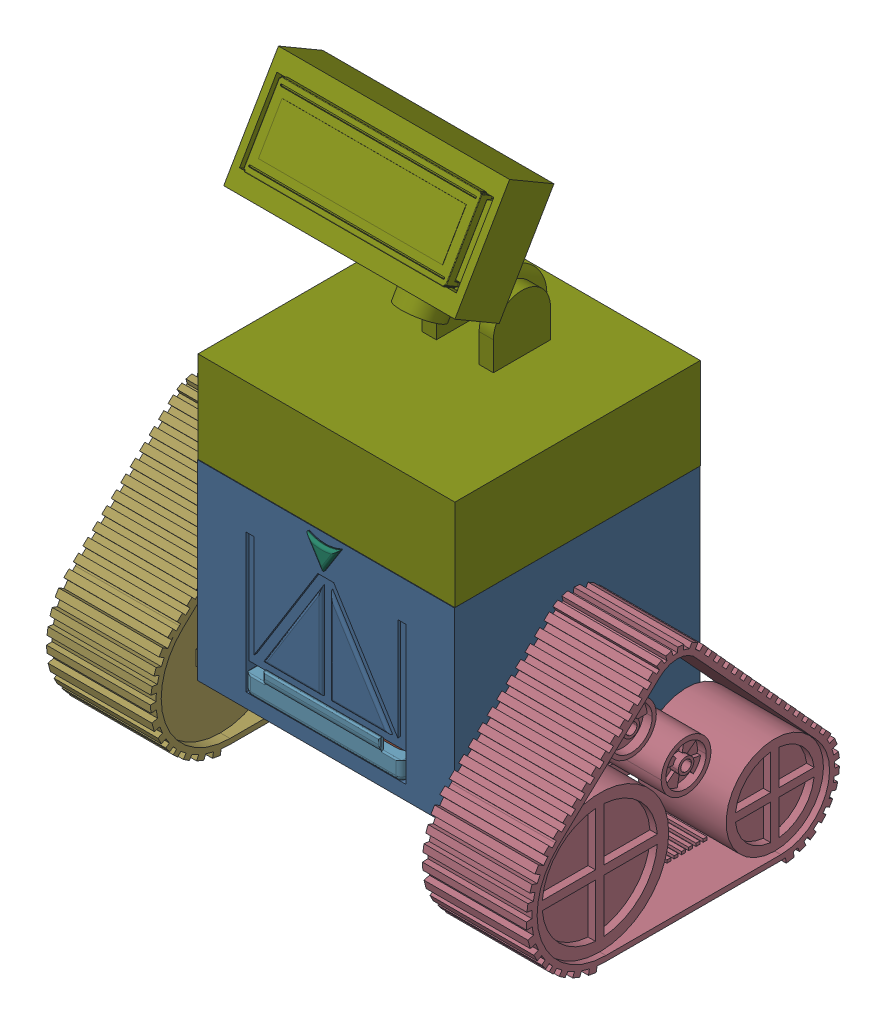
SolidWorks assembly Lower Body, configuration Default. Lengths in mm.
Overall size (168.14 212.39 109.67).
172 component instances, 52 part files, 15 mates.
Components (placement in the parent):
- Clock PCB.step-1: Clock PCB.step [Default] at (-3.837 -6.133 58.5856) size (81.95 80 25.5)
  - Board.step-1: Board.step [Default] at origin size (80 80 0.41)
    - Open CASCADE STEP translator 6.8 1.1.1.step-1: Open CASCADE STEP translator 6.8 1.1.1.step [Default] at (0 0 -0.4115) size (80 80 0.41)
  - XTAL1.step-1: XTAL1.step [Default] at origin size (11.36 4.66 3.61)
    - 6606830048.step-1: 6606830048.step [Default] at (28.0499 41.0499 0) size (11.36 4.66 1.01)
      - Extruded.step-1: Extruded.step [Default] at origin size (11.36 4.66 1.01)
    - 6606829968.step-1: 6606829968.step [Default] at (28.0499 41.0501 1) size (10.05 3.71 2.61)
      - Extruded-0.step-1: Extruded-0.step [Default] at origin size (10.05 3.71 2.61)
  - U2.step-1: U2.step [Default] at origin size (10.5 4.7 16.2)
    - 6606829888.step-1: 6606829888.step [Default] at (7.95 27.55 13.05) size (10.4 1.3 6.65)
      - Extruded-1.step-1: Extruded-1.step [Default] at origin size (10.4 1.3 6.65)
    - 6606829728.step-1: 6606829728.step [Default] at (7.95 25.9 3.5) size (10.5 4.7 9.55)
      - Extruded-2.step-1: Extruded-2.step [Default] at origin size (10.5 4.7 9.55)
  - U1.step-1: U1.step [Default] at origin size (63.7 16.03 14.45)
    - User_Library-ZIF-Socket-28-pin.step-1: User_Library-ZIF-Socket-28-pin.step [Default] at (43.5 28.05 0) x (1 0 0) z (0 0 1) size (63.7 16.03 14.45)
      - Contacts.step-1: Contacts.step [Default] at origin size (34.37 11.24 1.5)
      - Pins001.step-1: Pins001.step [Default] at origin size (33.87 8.47 3)
      - Screw002.step-1: Screw002.step [Default] at origin size (2.8 2.8 2)
      - Bottom-Shape.step-1: Bottom-Shape.step [Default] at origin size (50.4 15.02 8.11)
      - Lever-Tip.step-1: Lever-Tip.step [Default] at origin size (7 4.8 4.8)
      - Top-Shape.step-1: Top-Shape.step [Default] at origin size (50.4 15.02 3.8)
      - Push-Bar.step-1: Push-Bar.step [Default] at origin size (3.85 15.02 3.7)
      - Lever-Bar.step-1: Lever-Bar.step [Default] at origin size (19.2 11.43 1.62)
      - Screw001.step-1: Screw001.step [Default] at origin size (2.8 2.8 2)
  - Q1.step-1: Q1.step [Default] at origin size (3.05 4.08 12.8)
    - BC547-B.step-1: BC547-B.step [Default] at (72 53.1536 7) x (0 1 0) z (0 0 -1) size (4.08 3.05 12.8)
  - P3.step-1: P3.step [Default] at origin size (2.54 10.16 11.54)
    - 61300411121.step-1: 61300411121.step [Default] at (76.2999 22.6001 1.3) x (0 1 0) z (1 0 0) size (10.16 11.54 2.54)
      - 6130xx11121_PIN.step-1: 6130xx11121_PIN.step [Default] at (-3.81 1.5 0) x (1 0 0) z (0 -1 0) size (0.64 0.64 11.54)
      - 6130xx11121_PIN.step-2: 6130xx11121_PIN.step [Default] at (-1.27 1.5 0) x (1 0 0) z (0 -1 0) size (0.64 0.64 11.54)
      - 6130xx11121_PIN.step-3: 6130xx11121_PIN.step [Default] at (1.27 1.5 0) x (1 0 0) z (0 -1 0) size (0.64 0.64 11.54)
      - 6130xx11121_PIN.step-4: 6130xx11121_PIN.step [Default] at (3.81 1.5 0) x (1 0 0) z (0 -1 0) size (0.64 0.64 11.54)
      - 61300411121-3.step-1: 61300411121-3.step [Default] at origin size (10.16 2.54 2.54)
  - P2.step-1: P2.step [Default] at origin size (17.78 2.54 11.54)
    - 61300711121.step-1: 61300711121.step [Default] at (39.9599 3.8999 1.3) x (-1 0 0) z (0 1 0) size (17.78 11.54 2.54)
      - 6130xx11121_PIN-4.step-1: 6130xx11121_PIN-4.step [Default] at (-7.62 1.5 0) x (1 0 0) z (0 -1 0) size (0.64 0.64 11.54)
      - 6130xx11121_PIN-4.step-2: 6130xx11121_PIN-4.step [Default] at (-5.08 1.5 0) x (1 0 0) z (0 -1 0) size (0.64 0.64 11.54)
      - 6130xx11121_PIN-4.step-3: 6130xx11121_PIN-4.step [Default] at (-2.54 1.5 0) x (1 0 0) z (0 -1 0) size (0.64 0.64 11.54)
      - 6130xx11121_PIN-4.step-4: 6130xx11121_PIN-4.step [Default] at (0 1.5 0) x (1 0 0) z (0 -1 0) size (0.64 0.64 11.54)
      - 6130xx11121_PIN-4.step-5: 6130xx11121_PIN-4.step [Default] at (2.54 1.5 0) x (1 0 0) z (0 -1 0) size (0.64 0.64 11.54)
      - 6130xx11121_PIN-4.step-6: 6130xx11121_PIN-4.step [Default] at (5.08 1.5 0) x (1 0 0) z (0 -1 0) size (0.64 0.64 11.54)
      - 6130xx11121_PIN-4.step-7: 6130xx11121_PIN-4.step [Default] at (7.62 1.5 0) x (1 0 0) z (0 -1 0) size (0.64 0.64 11.54)
      - 61300711121-5.step-1: 61300711121-5.step [Default] at origin size (17.78 2.54 2.54)
  - P1.step-1: P1.step [Default] at origin size (30.48 2.54 11.54)
    - 61301211121.step-1: 61301211121.step [Default] at (41.3799 75.6999 1.3) x (-1 0 0) z (0 1 0) size (30.48 11.54 2.54)
      - 6130xx11121_PIN-6.step-1: 6130xx11121_PIN-6.step [Default] at (-13.97 1.5 0) x (1 0 0) z (0 -1 0) size (0.64 0.64 11.54)
      - 6130xx11121_PIN-6.step-2: 6130xx11121_PIN-6.step [Default] at (-11.43 1.5 0) x (1 0 0) z (0 -1 0) size (0.64 0.64 11.54)
      - 6130xx11121_PIN-6.step-3: 6130xx11121_PIN-6.step [Default] at (-8.89 1.5 0) x (1 0 0) z (0 -1 0) size (0.64 0.64 11.54)
      - 6130xx11121_PIN-6.step-4: 6130xx11121_PIN-6.step [Default] at (-6.35 1.5 0) x (1 0 0) z (0 -1 0) size (0.64 0.64 11.54)
      - 6130xx11121_PIN-6.step-5: 6130xx11121_PIN-6.step [Default] at (-3.81 1.5 0) x (1 0 0) z (0 -1 0) size (0.64 0.64 11.54)
      - 6130xx11121_PIN-6.step-6: 6130xx11121_PIN-6.step [Default] at (-1.27 1.5 0) x (1 0 0) z (0 -1 0) size (0.64 0.64 11.54)
      - 6130xx11121_PIN-6.step-7: 6130xx11121_PIN-6.step [Default] at (1.27 1.5 0) x (1 0 0) z (0 -1 0) size (0.64 0.64 11.54)
      - 6130xx11121_PIN-6.step-8: 6130xx11121_PIN-6.step [Default] at (3.81 1.5 0) x (1 0 0) z (0 -1 0) size (0.64 0.64 11.54)
      - 6130xx11121_PIN-6.step-9: 6130xx11121_PIN-6.step [Default] at (6.35 1.5 0) x (1 0 0) z (0 -1 0) size (0.64 0.64 11.54)
      - 6130xx11121_PIN-6.step-10: 6130xx11121_PIN-6.step [Default] at (8.89 1.5 0) x (1 0 0) z (0 -1 0) size (0.64 0.64 11.54)
      - 6130xx11121_PIN-6.step-11: 6130xx11121_PIN-6.step [Default] at (11.43 1.5 0) x (1 0 0) z (0 -1 0) size (0.64 0.64 11.54)
      - 6130xx11121_PIN-6.step-12: 6130xx11121_PIN-6.step [Default] at (13.97 1.5 0) x (1 0 0) z (0 -1 0) size (0.64 0.64 11.54)
      - 61301211121-7.step-1: 61301211121-7.step [Default] at origin size (30.48 2.54 2.54)
  - KEY5.step-1: KEY5.step [Default] at origin size (7.8 5.99 8.11)
    - Switch_TE_1825910-2_eec.step-1: Switch_TE_1825910-2_eec.step [Default] at (68.1 13.85 0) size (7.8 5.99 8.11)
      - Body.step-1: Body.step [Default] at (0 0 4.3) x (0 -1 0) z (0 0 1) size (5.99 5.99 3.9)
      - button.step-1: button.step [Default] at (0 0 4.3) x (0 -1 0) z (0 0 1) size (3.51 3.51 1.1)
      - cover.step-1: cover.step [Default] at (0 0 4.3) x (0 -1 0) z (0 0 1) size (5.99 5.99 0.1)
      - leads.step-1: leads.step [Default] at (0 0 4.3) x (0 -1 0) z (0 0 1) size (5.21 7.8 4.81)
      - circle.step-1: circle.step [Default] at (-2.6803 2.6863 3.6) size (0.4 0.4 0)
      - TE_Connectivity.step-1: TE_Connectivity.step [Default] at (-0.1925 -2.4218 3.6) size (2.27 0.85 0.01)
  - KEY4.step-1: KEY4.step [Default] at origin size (7.8 5.99 8.11)
    - Switch_TE_1825910-2_eec.step-1: Switch_TE_1825910-2_eec.step [Default] at (50 55 0) size (7.8 5.99 8.11)
      - Body.step-1: Body.step [Default] at (0 0 4.3) x (0 -1 0) z (0 0 1) size (5.99 5.99 3.9)
      - button.step-1: button.step [Default] at (0 0 4.3) x (0 -1 0) z (0 0 1) size (3.51 3.51 1.1)
      - cover.step-1: cover.step [Default] at (0 0 4.3) x (0 -1 0) z (0 0 1) size (5.99 5.99 0.1)
      - leads.step-1: leads.step [Default] at (0 0 4.3) x (0 -1 0) z (0 0 1) size (5.21 7.8 4.81)
      - circle.step-1: circle.step [Default] at (-2.6803 2.6863 3.6) size (0.4 0.4 0)
      - TE_Connectivity.step-1: TE_Connectivity.step [Default] at (-0.1925 -2.4218 3.6) size (2.27 0.85 0.01)
  - KEY3.step-1: KEY3.step [Default] at origin size (7.8 5.99 8.11)
    - Switch_TE_1825910-2_eec.step-1: Switch_TE_1825910-2_eec.step [Default] at (30 55 0) size (7.8 5.99 8.11)
      - Body.step-1: Body.step [Default] at (0 0 4.3) x (0 -1 0) z (0 0 1) size (5.99 5.99 3.9)
      - button.step-1: button.step [Default] at (0 0 4.3) x (0 -1 0) z (0 0 1) size (3.51 3.51 1.1)
      - cover.step-1: cover.step [Default] at (0 0 4.3) x (0 -1 0) z (0 0 1) size (5.99 5.99 0.1)
      - leads.step-1: leads.step [Default] at (0 0 4.3) x (0 -1 0) z (0 0 1) size (5.21 7.8 4.81)
      - circle.step-1: circle.step [Default] at (-2.6803 2.6863 3.6) size (0.4 0.4 0)
      - TE_Connectivity.step-1: TE_Connectivity.step [Default] at (-0.1925 -2.4218 3.6) size (2.27 0.85 0.01)
  - KEY2.step-1: KEY2.step [Default] at origin size (7.8 5.99 8.11)
    - Switch_TE_1825910-2_eec.step-1: Switch_TE_1825910-2_eec.step [Default] at (40 45 0) size (7.8 5.99 8.11)
      - Body.step-1: Body.step [Default] at (0 0 4.3) x (0 -1 0) z (0 0 1) size (5.99 5.99 3.9)
      - button.step-1: button.step [Default] at (0 0 4.3) x (0 -1 0) z (0 0 1) size (3.51 3.51 1.1)
      - cover.step-1: cover.step [Default] at (0 0 4.3) x (0 -1 0) z (0 0 1) size (5.99 5.99 0.1)
      - leads.step-1: leads.step [Default] at (0 0 4.3) x (0 -1 0) z (0 0 1) size (5.21 7.8 4.81)
      - circle.step-1: circle.step [Default] at (-2.6803 2.6863 3.6) size (0.4 0.4 0)
      - TE_Connectivity.step-1: TE_Connectivity.step [Default] at (-0.1925 -2.4218 3.6) size (2.27 0.85 0.01)
  - KEY1.step-1: KEY1.step [Default] at origin size (7.8 5.99 8.11)
    - Switch_TE_1825910-2_eec.step-1: Switch_TE_1825910-2_eec.step [Default] at (40 65 0) size (7.8 5.99 8.11)
      - Body.step-1: Body.step [Default] at (0 0 4.3) x (0 -1 0) z (0 0 1) size (5.99 5.99 3.9)
      - button.step-1: button.step [Default] at (0 0 4.3) x (0 -1 0) z (0 0 1) size (3.51 3.51 1.1)
      - cover.step-1: cover.step [Default] at (0 0 4.3) x (0 -1 0) z (0 0 1) size (5.99 5.99 0.1)
      - leads.step-1: leads.step [Default] at (0 0 4.3) x (0 -1 0) z (0 0 1) size (5.21 7.8 4.81)
      - circle.step-1: circle.step [Default] at (-2.6803 2.6863 3.6) size (0.4 0.4 0)
      - TE_Connectivity.step-1: TE_Connectivity.step [Default] at (-0.1925 -2.4218 3.6) size (2.27 0.85 0.01)
  - JST2.step-1: JST2.step [Default] at origin size (4.7 6 10.05)
    - Conn_TE_Connectivity_440054-2_eec.step-1: Conn_TE_Connectivity_440054-2_eec.step [Default] at (72.85 68.85 0) x (0 -1 0) z (0 0 1) size (6 4.7 10.05)
      - 1.step-1: 1.step [Default] at (0 -0.6 6.05) size (2.5 2.35 8.8)
      - 2.step-1: 2.step [Default] at (0 -0.6 6.05) size (0.9 0.1 1.08)
      - 3.step-1: 3.step [Default] at (0 -0.6 6.05) size (6 4.7 6.35)
      - TE_connectivity_Logo_1_(2).step-1: TE_connectivity_Logo_1_(2).step [Default] at (2.901 6.9182 0.6322) x (0 -1 0) z (1 0 0) size (1.49 0.53 0.1)
  - JST1.step-1: JST1.step [Default] at origin size (6 4.7 10.05)
    - Conn_TE_Connectivity_440054-2_eec.step-1: Conn_TE_Connectivity_440054-2_eec.step [Default] at (10.55 4.25 0) x (-1 0 0) z (0 0 1) size (6 4.7 10.05)
      - 1.step-1: 1.step [Default] at (0 -0.6 6.05) size (2.5 2.35 8.8)
      - 2.step-1: 2.step [Default] at (0 -0.6 6.05) size (0.9 0.1 1.08)
      - 3.step-1: 3.step [Default] at (0 -0.6 6.05) size (6 4.7 6.35)
      - TE_connectivity_Logo_1_(2).step-1: TE_connectivity_Logo_1_(2).step [Default] at (2.901 6.9182 0.6322) x (0 -1 0) z (1 0 0) size (1.49 0.53 0.1)
  - JST3.step-1: JST3.step [Default] at origin size (7.9 4.5 9.4)
    - 6606829248.step-1: 6606829248.step [Default] at (11.9 70.55 -3.4) size (0.5 0.5 8.45)
      - Extruded-8.step-1: Extruded-8.step [Default] at origin size (0.5 0.5 8.45)
    - 6606829248.step-2: 6606829248.step [Default] at (7.9 70.55 -3.4) size (0.5 0.5 8.45)
      - Extruded-8.step-1: Extruded-8.step [Default] at origin size (0.5 0.5 8.45)
    - 6606829248.step-3: 6606829248.step [Default] at (9.9 70.55 -3.4) size (0.5 0.5 8.45)
      - Extruded-8.step-1: Extruded-8.step [Default] at origin size (0.5 0.5 8.45)
    - 6606828928.step-1: 6606828928.step [Default] at (9.9 70.2 0) size (6.6 4.1 1.75)
      - Extruded-9.step-1: Extruded-9.step [Default] at origin size (6.6 4.1 1.75)
    - 6606828768.step-1: 6606828768.step [Default] at (9.9 68.875 0) size (7.9 2.25 6)
      - Extruded-10.step-1: Extruded-10.step [Default] at origin size (7.9 2.25 6)
    - 6606828608.step-1: 6606828608.step [Default] at (7.525 71.525 0) size (3.15 1.45 6)
      - Extruded-11.step-1: Extruded-11.step [Default] at origin size (3.15 1.45 6)
    - 6606828448.step-1: 6606828448.step [Default] at (6.275 70.4 0) size (0.65 0.8 4.1)
      - Extruded-12.step-1: Extruded-12.step [Default] at origin size (0.65 0.8 4.1)
    - 6606828448.step-2: 6606828448.step [Default] at (13.525 70.4 0) size (0.65 0.8 4.1)
      - Extruded-12.step-1: Extruded-12.step [Default] at origin size (0.65 0.8 4.1)
    - 6606828208.step-1: 6606828208.step [Default] at (12.275 71.525 0) size (3.15 1.45 6)
      - Extruded-13.step-1: Extruded-13.step [Default] at origin size (3.15 1.45 6)
  - C6.step-1: C6.step [Default] at origin size (8 8 14.5)
    - Aluminum_electrolytic_capacitor_radial_D8_H11.5_PinD0.6_Pitch3.5_nominal_black.step-1: Aluminum_electrolytic_capacitor_radial_D8_H11.5_PinD0.6_Pitch3.5_nominal_black.step [Default] at (64.35 73.55 0) x (-1 0 0) z (0 0 1) size (1.1 2.07 11.1)
    - Aluminum_electrolytic_capacitor_radial_D8_H11.5_PinD0.6_Pitch3.5_nominal_black-14.step-1: Aluminum_electrolytic_capacitor_radial_D8_H11.5_PinD0.6_Pitch3.5_nominal_black-14.step [Default] at (64.35 73.55 0) x (-1 0 0) z (0 0 1) size (7.86 8 11.1)
    - Aluminum_electrolytic_capacitor_radial_D8_H11.5_PinD0.6_Pitch3.5_nominal_black-15.step-1: Aluminum_electrolytic_capacitor_radial_D8_H11.5_PinD0.6_Pitch3.5_nominal_black-15.step [Default] at (64.35 73.55 0) x (-1 0 0) z (0 0 1) size (7.8 7.8 10.9)
    - Aluminum_electrolytic_capacitor_radial_D8_H11.5_PinD0.6_Pitch3.5_nominal_black-16.step-1: Aluminum_electrolytic_capacitor_radial_D8_H11.5_PinD0.6_Pitch3.5_nominal_black-16.step [Default] at (64.35 73.55 0) x (-1 0 0) z (0 0 1) size (7.4 7.4 1.6)
    - Aluminum_electrolytic_capacitor_radial_D8_H11.5_PinD0.6_Pitch3.5_nominal_black-17.step-1: Aluminum_electrolytic_capacitor_radial_D8_H11.5_PinD0.6_Pitch3.5_nominal_black-17.step [Default] at (64.35 73.55 0) x (-1 0 0) z (0 0 1) size (4.1 0.6 3)
  - C5.step-1: C5.step [Default] at origin size (8 8 14.5)
    - Aluminum_electrolytic_capacitor_radial_D8_H11.5_PinD0.6_Pitch3.5_nominal_black.step-1: Aluminum_electrolytic_capacitor_radial_D8_H11.5_PinD0.6_Pitch3.5_nominal_black.step [Default] at (65.05 5.25 0) size (1.1 2.07 11.1)
    - Aluminum_electrolytic_capacitor_radial_D8_H11.5_PinD0.6_Pitch3.5_nominal_black-14.step-1: Aluminum_electrolytic_capacitor_radial_D8_H11.5_PinD0.6_Pitch3.5_nominal_black-14.step [Default] at (65.05 5.25 0) size (7.86 8 11.1)
    - Aluminum_electrolytic_capacitor_radial_D8_H11.5_PinD0.6_Pitch3.5_nominal_black-15.step-1: Aluminum_electrolytic_capacitor_radial_D8_H11.5_PinD0.6_Pitch3.5_nominal_black-15.step [Default] at (65.05 5.25 0) size (7.8 7.8 10.9)
    - Aluminum_electrolytic_capacitor_radial_D8_H11.5_PinD0.6_Pitch3.5_nominal_black-16.step-1: Aluminum_electrolytic_capacitor_radial_D8_H11.5_PinD0.6_Pitch3.5_nominal_black-16.step [Default] at (65.05 5.25 0) size (7.4 7.4 1.6)
    - Aluminum_electrolytic_capacitor_radial_D8_H11.5_PinD0.6_Pitch3.5_nominal_black-17.step-1: Aluminum_electrolytic_capacitor_radial_D8_H11.5_PinD0.6_Pitch3.5_nominal_black-17.step [Default] at (65.05 5.25 0) size (4.1 0.6 3)
  - C4.step-1: C4.step [Default] at origin size (5.99 5.99 8.89)
    - Cap_Murata_RCE5C2A3R0C0K1H03B_eec.step-1: Cap_Murata_RCE5C2A3R0C0K1H03B_eec.step [Default] at (13.7 39.4 0) x (1 0 0) z (0 0 1) size (5.99 5.99 8.89)
      - Body.step-1: Body.step [Default] at origin size (5.99 5.99 3.9)
      - leads-18.step-1: leads-18.step [Default] at origin size (5.5 0.5 6.65)
      - logo.step-1: logo.step [Default] at (0 -1.25 8.5) x (1 0 0) z (0 -1 0) size (1.98 0.46 0.01)
  - C3.step-1: C3.step [Default] at origin size (5.99 5.99 8.89)
    - Cap_Murata_RCE5C2A3R0C0K1H03B_eec.step-1: Cap_Murata_RCE5C2A3R0C0K1H03B_eec.step [Default] at (13.65 43.7 0) x (1 0 0) z (0 0 1) size (5.99 5.99 8.89)
      - Body.step-1: Body.step [Default] at origin size (5.99 5.99 3.9)
      - leads-18.step-1: leads-18.step [Default] at origin size (5.5 0.5 6.65)
      - logo.step-1: logo.step [Default] at (0 -1.25 8.5) x (1 0 0) z (0 -1 0) size (1.98 0.46 0.01)
  - C2.step-1: C2.step [Default] at origin size (8 8 14.5)
    - Aluminum_electrolytic_capacitor_radial_D8_H11.5_PinD0.6_Pitch3.5_nominal_black.step-1: Aluminum_electrolytic_capacitor_radial_D8_H11.5_PinD0.6_Pitch3.5_nominal_black.step [Default] at (17.55 14.1 0) size (1.1 2.07 11.1)
    - Aluminum_electrolytic_capacitor_radial_D8_H11.5_PinD0.6_Pitch3.5_nominal_black-14.step-1: Aluminum_electrolytic_capacitor_radial_D8_H11.5_PinD0.6_Pitch3.5_nominal_black-14.step [Default] at (17.55 14.1 0) size (7.86 8 11.1)
    - Aluminum_electrolytic_capacitor_radial_D8_H11.5_PinD0.6_Pitch3.5_nominal_black-15.step-1: Aluminum_electrolytic_capacitor_radial_D8_H11.5_PinD0.6_Pitch3.5_nominal_black-15.step [Default] at (17.55 14.1 0) size (7.8 7.8 10.9)
    - Aluminum_electrolytic_capacitor_radial_D8_H11.5_PinD0.6_Pitch3.5_nominal_black-16.step-1: Aluminum_electrolytic_capacitor_radial_D8_H11.5_PinD0.6_Pitch3.5_nominal_black-16.step [Default] at (17.55 14.1 0) size (7.4 7.4 1.6)
    - Aluminum_electrolytic_capacitor_radial_D8_H11.5_PinD0.6_Pitch3.5_nominal_black-17.step-1: Aluminum_electrolytic_capacitor_radial_D8_H11.5_PinD0.6_Pitch3.5_nominal_black-17.step [Default] at (17.55 14.1 0) size (4.1 0.6 3)
  - C1.step-1: C1.step [Default] at origin size (8 8 14.5)
    - Aluminum_electrolytic_capacitor_radial_D8_H11.5_PinD0.6_Pitch3.5_nominal_black.step-1: Aluminum_electrolytic_capacitor_radial_D8_H11.5_PinD0.6_Pitch3.5_nominal_black.step [Default] at (7.05 14.5 0) size (1.1 2.07 11.1)
    - Aluminum_electrolytic_capacitor_radial_D8_H11.5_PinD0.6_Pitch3.5_nominal_black-14.step-1: Aluminum_electrolytic_capacitor_radial_D8_H11.5_PinD0.6_Pitch3.5_nominal_black-14.step [Default] at (7.05 14.5 0) size (7.86 8 11.1)
    - Aluminum_electrolytic_capacitor_radial_D8_H11.5_PinD0.6_Pitch3.5_nominal_black-15.step-1: Aluminum_electrolytic_capacitor_radial_D8_H11.5_PinD0.6_Pitch3.5_nominal_black-15.step [Default] at (7.05 14.5 0) size (7.8 7.8 10.9)
    - Aluminum_electrolytic_capacitor_radial_D8_H11.5_PinD0.6_Pitch3.5_nominal_black-16.step-1: Aluminum_electrolytic_capacitor_radial_D8_H11.5_PinD0.6_Pitch3.5_nominal_black-16.step [Default] at (7.05 14.5 0) size (7.4 7.4 1.6)
    - Aluminum_electrolytic_capacitor_radial_D8_H11.5_PinD0.6_Pitch3.5_nominal_black-17.step-1: Aluminum_electrolytic_capacitor_radial_D8_H11.5_PinD0.6_Pitch3.5_nominal_black-17.step [Default] at (7.05 14.5 0) size (4.1 0.6 3)
  - Free-Models.step-1: Free-Models.step [Default] at origin size (34.6 9.68 7.3)
    - atmega328p-pu.step-1: atmega328p-pu.step [Default] at (59.217 28 11) x (-1 0 0) z (0 1 0) size (34.6 7.3 9.68)
- Part46^Lower Body-1: Part46^Lower Body [Default] at origin size (90 95.83 86) (virtual)
- Matrix Keypad 12 Key (4X3)-3: Matrix Keypad 12 Key (4X3) [Default] at (36.3513 -10.233 60.678) x (1 0 0) z (0 1 0) size (54 77 1.31)
- wheel 2-2: wheel 2 [Default] at (-18.6112 -22.8736 33.5298) size (56.04 84.58 109.67)
- Mirrorwheel 2-5: Mirrorwheel 2 [Default] at (91.0372 -22.8736 33.5298) x (-1 0 0) z (0 0 -1) size (56.04 84.58 109.67)
- Part4^Lower Body-1: Part4^Lower Body [Default] at (36.3513 -10.233 60.678) x (-1 0 0) z (0 -1 0) size (55 82.09 11) (virtual)
- Part5^Lower Body-1: Part5^Lower Body [Default] at (0 0 101.5856) size (12.45 10.37 39.83) (virtual)
- upper part-1: upper part [Default] at (71.8557 119.3769 -12.5727) x (-1 0 0) z (0 0 1) size (90 115.82 86)
Mates (geometry in assembly coordinates):
- Perpendicular1: perpendicular: plane of Part46^Lower Body-1 through (-8.787 -22.233 101.5856) normal (0 -1 0); plane of wheel 2-2 through (-10.3877 -22.301 50.7401) normal (0 0 -1)
- InPlace1: in place: plane of ? through (70.3473 -28.3571 185.2121) normal (0 -1 0); plane of ? through (0 -28.3571 0) normal (0 -1 0); moOrthogonalPlaneRef_w of ? through (70.3473 -28.3571 185.2121) normal (0 -1 0); plane of ? through (0 -28.3571 0) normal (0 0 -1); plane of ? through (70.3473 -28.3571 185.2121) normal (0 -1 0); plane of ? through (0 -28.3571 0) normal (-1 0 0); plane of Matrix Keypad 12 Key (4X3)-3 through (36.3513 -10.233 60.678) normal (0 -1 0); unknown of Part4^Lower Body-1
- Coincident8: coincident aligned: plane of ?; plane of ?
- Coincident9: coincident aligned: moOrthogonalPlaneRef_w of Matrix Keypad 12 Key (4X3)-3 through (36.3513 -10.233 60.678) normal (0 0 -1); plane of Part4^Initial-1 through (36.3513 -10.233 60.678) normal (0 0 -1)
- Coincident10: coincident anti-aligned: moOrthogonalPlaneRef_w of Matrix Keypad 12 Key (4X3)-3 through (36.3513 -10.233 60.678) normal (1 0 0); plane of Part4^Initial-1 through (36.3513 -10.233 60.678) normal (-1 0 0)
- Parallel2: parallel anti-aligned: plane of Part46^Lower Body-1 through (8.213 -6.233 21.5856) normal (1 0 0); plane of Part4^Initial-1 through (8.8513 -17.233 102.635) normal (-1 0 0)
- Parallel3: parallel anti-aligned: plane of Part46^Lower Body-1 through (64.213 -6.233 21.5856) normal (-1 0 0); plane of Part4^Initial-1 through (63.8513 -17.233 102.635) normal (1 0 0)
- Distance1: distance = 0 mm anti-aligned: plane of Part4^Initial-1 through (36.3513 -17.233 60.678) normal (0 -1 0); plane of Part46^Lower Body-1 through (6.213 -17.233 21.5856) normal (0 1 0)
- InPlace2: in place: plane of Part46^Lower Body-1 through (0 0 101.5856) normal (0 0 1); plane of Part5^Lower Body-1 through (0 0 101.5856) normal (0 0 1); plane of Part46^Lower Body-1 through (0 0 101.5856) normal (0 0 1); plane of Part5^Lower Body-1 through (0 0 101.5856) normal (0 1 0); plane of Part46^Lower Body-1 through (0 0 101.5856) normal (0 0 1); plane of Part5^Lower Body-1 through (0 0 101.5856) normal (1 0 0); plane of Part46^Lower Body-1 through (0 0 101.5856) normal (0 0 1); unknown of Part5^Lower Body-1
- Coincident14: coincident aligned: plane of ?; plane of ?
- Coincident15: coincident aligned: moOrthogonalPlaneRef_w of Part46^Lower Body-1 through (0 0 101.5856) normal (0 1 0); plane of Part5^Initial-1 through (0 0 101.5856) normal (0 1 0)
- Coincident16: coincident anti-aligned: moOrthogonalPlaneRef_w of Part46^Lower Body-1 through (0 0 101.5856) normal (-1 0 0); plane of Part5^Initial-1 through (0 0 101.5856) normal (1 0 0)
- Coincident1: coincident anti-aligned: plane of Part46^Lower Body-1 through (-8.787 44.767 101.5856) normal (0 1 0); plane of upper part-1 through (36.195 44.767 58.3799) normal (0 -1 0)
- Lock4: lock: unknown of Part46^Lower Body-1; unknown of upper part-1
- Lock5: lock: unknown of Part46^Lower Body-1; unknown of wheel 2-2
